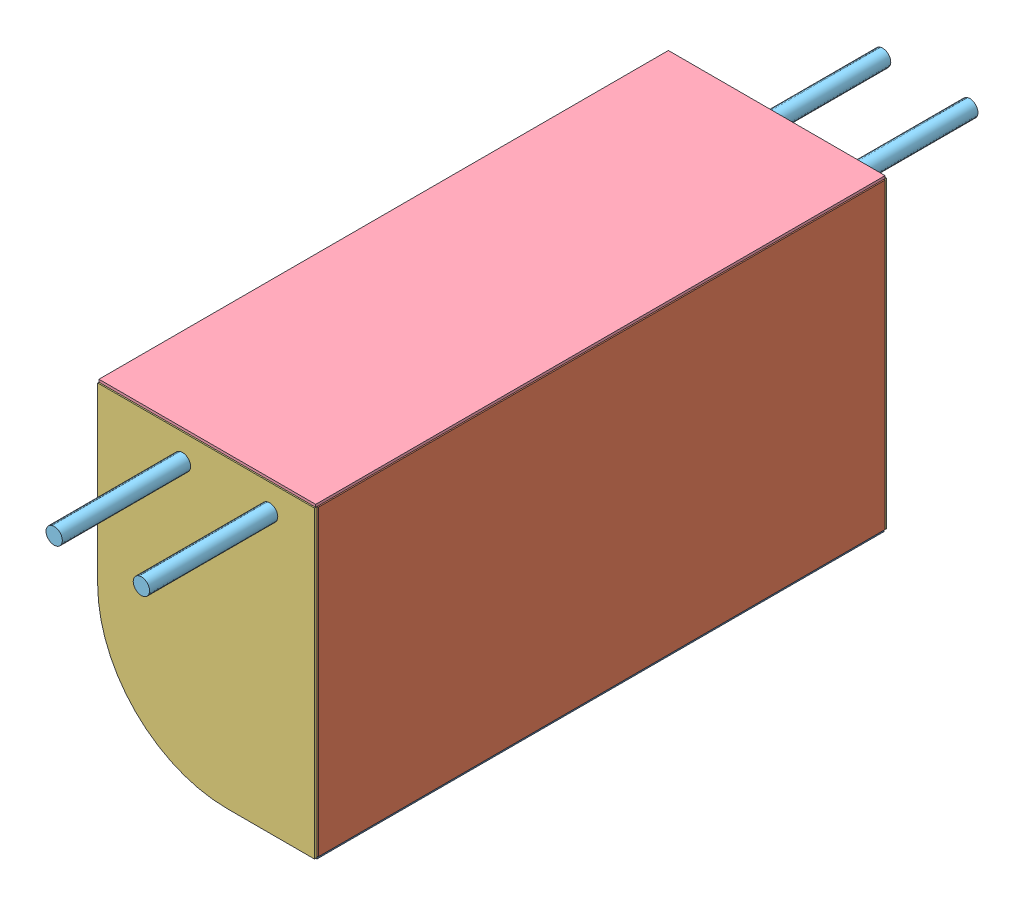
SolidWorks assembly SideTop, configuration Default. Lengths in mm.
Overall size (127.75 179.3 482.6).
7 component instances, 5 part files, 20 mates.
Components (placement in the parent):
- 701-PlateCurved-1: 701-PlateCurved [Default] at origin size (127 177.8 330.2)
- 703-PlateBack-1: 703-PlateBack [Default] at origin size (1.5 176.3 330.2)
- 702-PlateSide-1: 702-PlateSide [Default] at (0 0 165.1) size (126.25 177.05 1.5)
- 702-PlateSide-2: 702-PlateSide [Default] at (0 0 -166.6) size (126.25 177.05 1.5)
- 704-PlateBottom-1: 704-PlateBottom [Default] at (0 1168.4 0) x (-1 0 0) z (0 1 0) size (126.25 331.7 1.5)
- 103-RodYokes-1: 103-RodYokes [Default] at (-88.2125 990.6 0) size (9.53 9.52 482.6)
- 103-RodYokes-2: 103-RodYokes [Default] at (-139.0125 990.6 0) size (9.53 9.52 482.6)
Mates (geometry in assembly coordinates):
- InPlace1: in place: plane of ?
- Coincident1: coincident aligned: plane of 701-PlateCurved-1; plane of ?
- Coincident2: coincident aligned: plane of ? through (0 0 0) normal (0 1 0)
- Coincident3: coincident anti-aligned: plane of ? through (0 0 0) normal (1 0 0)
- InPlace2: in place: unknown of ?
- Coincident4: coincident aligned: plane of 703-PlateBack-1; plane of ?
- Coincident5: coincident aligned: plane of ? through (0 0 0) normal (0 1 0)
- Coincident6: coincident anti-aligned: plane of ? through (0 0 0) normal (1 0 0)
- InPlace3: in place: plane of ? through (-468.975 1066.8 165.1) normal (0 0 1); unknown of 702-PlateSide-1
- Coincident7: coincident aligned: plane of 701-PlateCurved-1; plane of 702-PlateSide-1
- Coincident8: coincident aligned: moOrthogonalPlaneRef_w of 701-PlateCurved-1 through (0 0 165.1) axis (0 1 0); plane of 702-PlateSide-1 through (0 0 165.1) normal (0 1 0)
- Coincident9: coincident anti-aligned: moOrthogonalPlaneRef_w of 701-PlateCurved-1 through (0 0 165.1) axis (-1 0 0); plane of 702-PlateSide-1 through (0 0 165.1) normal (1 0 0)
- InPlace4: in place: plane of ? through (-545.175 1168.4 165.1) normal (0 1 0); unknown of 704-PlateBottom-1
- Coincident10: coincident aligned: plane of 701-PlateCurved-1; plane of 704-PlateBottom-1
- Coincident11: coincident aligned: moOrthogonalPlaneRef_w of 701-PlateCurved-1 through (0 1168.4 0) axis (0 0 1); plane of 704-PlateBottom-1
- Coincident12: coincident anti-aligned: moOrthogonalPlaneRef_w of 701-PlateCurved-1 through (-1000 0 1168.4) axis (0 1 0); plane of 704-PlateBottom-1
- Concentric1: concentric aligned: cylinder of 702-PlateSide-1 through (-444.2625 1153.3 166.6) axis (0 0 -1) radius 4.7625; cylinder of 103-RodYokes-1 through (-444.2625 1153.3 241.3) axis (0 0 -1) radius 4.7625
- Coincident13: coincident aligned: plane of 103-RodYokes-1 through (-88.2125 990.6 0) normal (0 0 1); plane of assembly through (0 0 0) normal (0 0 1)
- Coincident14: coincident aligned: plane of 103-RodYokes-2 through (-139.0125 990.6 0) normal (0 0 1); plane of assembly through (0 0 0) normal (0 0 1)
- Concentric2: concentric aligned: cylinder of 702-PlateSide-1 through (-495.0625 1153.3 166.6) axis (0 0 -1) radius 4.7625; cylinder of 103-RodYokes-2 through (-495.0625 1153.3 241.3) axis (0 0 -1) radius 4.7625
